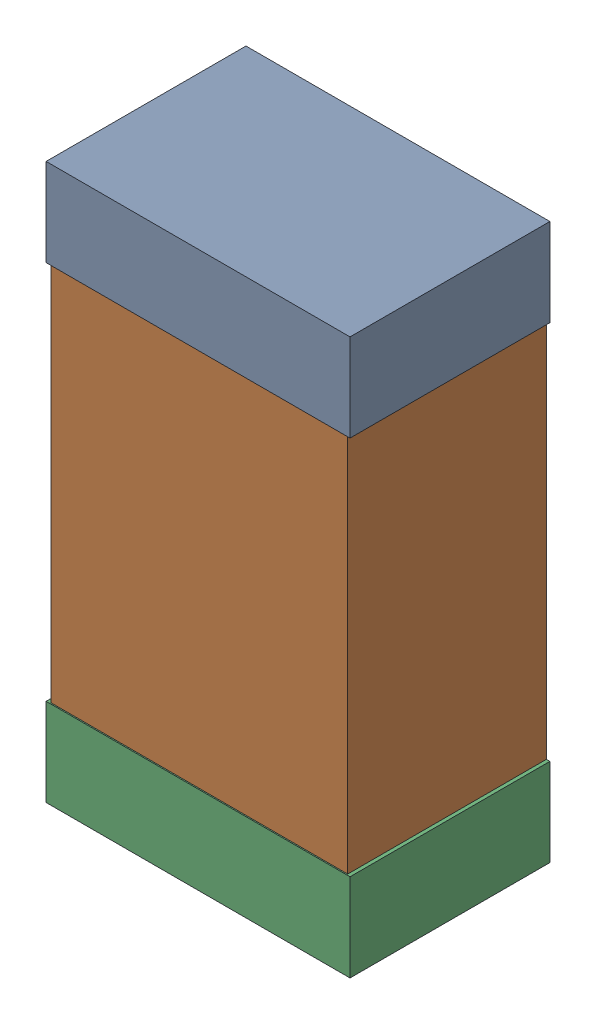
SolidWorks assembly 35.7KKanaloa_v2.0.0_Power, configuration Default. Lengths in mm.
Overall size (1.3 2.38 0.85).
6 component instances, 2 part files, 0 mates.
Components (placement in the parent):
- 330415056-1: 330415056 [Default] at (126.8208 93.6064 0) size (1.3 0.38 0.85)
  - Extruded_2-1: Extruded_2 [Default] at origin size (1.3 0.38 0.85)
- 334787376-1: 334787376 [Default] at (126.8208 92.6064 0) size (1.27 2.2 0.85)
  - Extruded_16-1: Extruded_16 [Default] at origin size (1.27 2.2 0.85)
- 330415056-2: 330415056 [Default] at (126.8208 91.6064 0) size (1.3 0.38 0.85)
  - Extruded_2-1: Extruded_2 [Default] at origin size (1.3 0.38 0.85)
